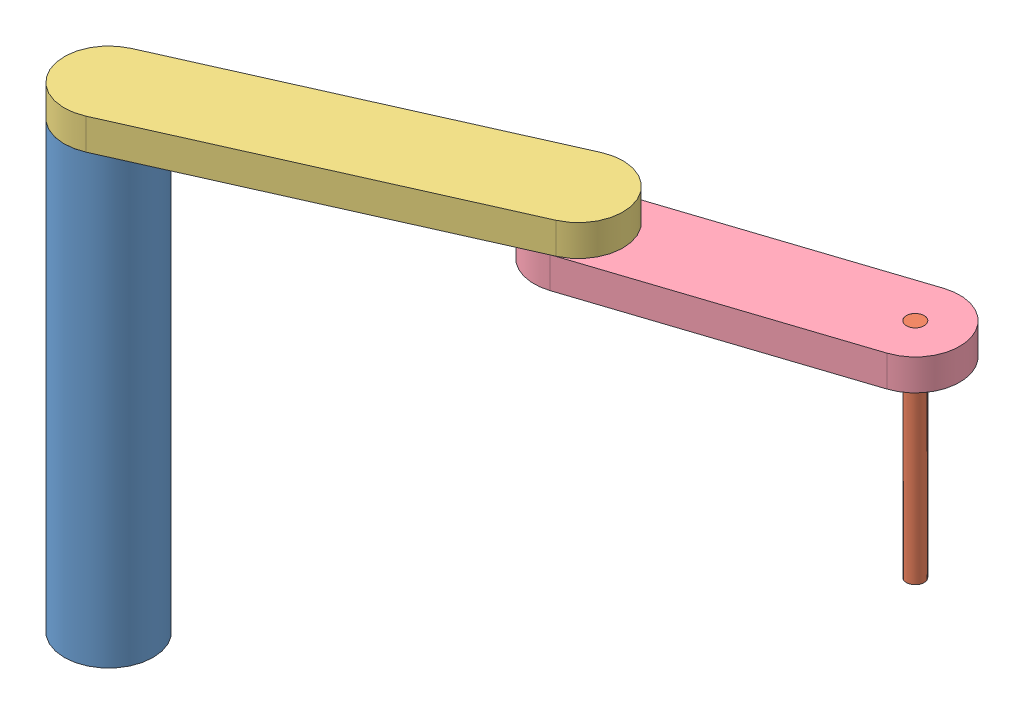
SolidWorks assembly Assem1, configuration Default. Lengths in mm.
Overall size (1559.12 1070 770.71).
4 component instances, 4 part files, 6 mates.
Components (placement in the parent):
- base-1: base [Default] at (-16.6414 89.91 927.1024) size (200 1000 200)
- D3-1: D3 [Default] at (1284.2602 589.91 414.6121) x (0.80687 0 -0.590728) z (0.590728 0 0.80687) size (40 500 40)
- L1-1: L1 [Default] at (714.1323 1089.91 601.5724) x (-0.913467 0 0.406913) z (-0.406913 0 -0.913467) size (1000 90 200)
- L2-1: L2 [Default] at (714.1323 1019.91 601.5724) x (0.950213 0 -0.3116) z (0.3116 0 0.950213) size (800 70 200)
Mates (geometry in assembly coordinates):
- Coincident2: coincident anti-aligned: plane of base-1 through (-16.6414 1069.91 927.1024) normal (0 1 0); plane of L1-1 through (-16.6414 1069.91 927.1024) normal (0 -1 0)
- Concentric1: concentric aligned: cylinder of base-1 through (-16.6414 1069.91 927.1024) axis (0 1 0) radius 10; cylinder of L1-1 through (-16.6414 1069.91 927.1024) axis (0 1 0) radius 10
- Coincident4: coincident anti-aligned: plane of L1-1 through (714.1323 1069.91 601.5724) normal (0 -1 0); plane of L2-1 through (714.1323 1069.91 601.5724) normal (0 1 0)
- Concentric2: concentric aligned: cylinder of L1-1 through (714.1323 1069.91 601.5724) axis (0 1 0) radius 10; cylinder of L2-1 through (714.1323 1069.91 601.5724) axis (0 1 0) radius 10
- Concentric3: concentric anti-aligned: cylinder of D3-1 through (1284.2602 1089.91 414.6121) axis (0 -1 0) radius 20; cylinder of L2-1 through (1284.2602 1019.91 414.6121) axis (0 1 0) radius 20
- LimitDistance1: limit distance = 0 mm aligned: plane of L2-1 through (714.1323 1089.91 601.5724) normal (0 1 0); plane of D3-1 through (1284.2602 1089.91 414.6121) normal (0 1 0)
